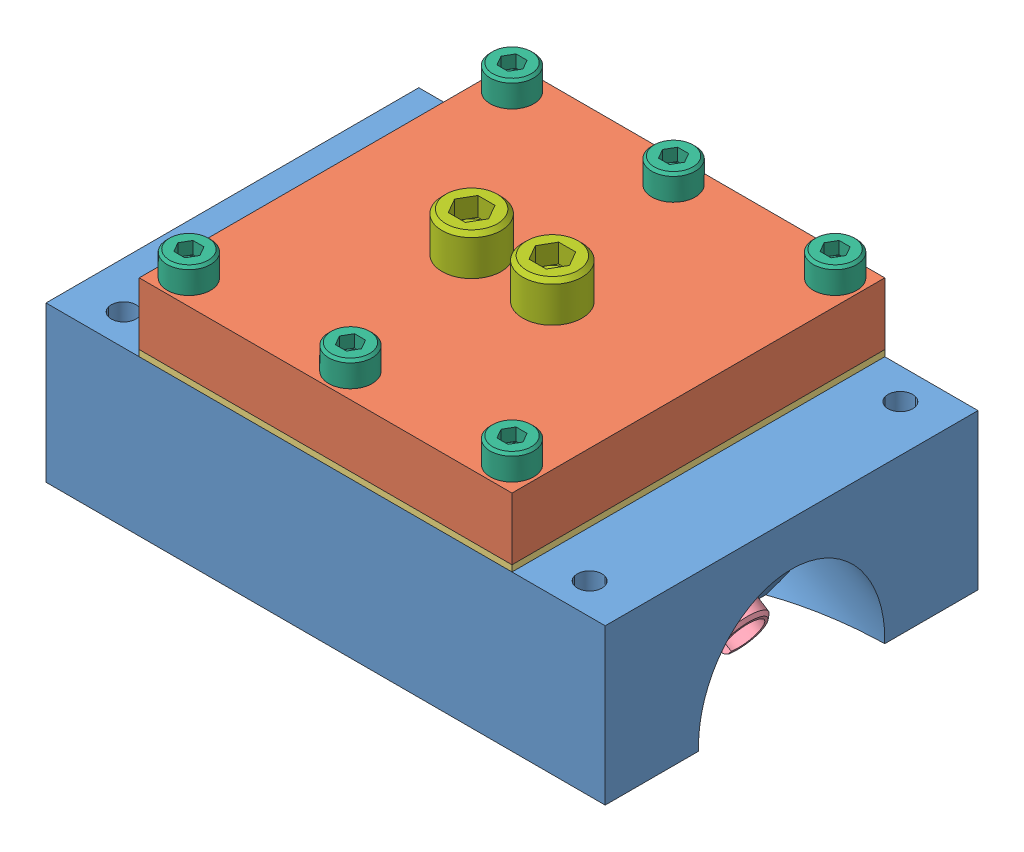
SolidWorks assembly assembly of final, configuration Default. Lengths in mm.
Overall size (90 48.33 60).
13 component instances, 7 part files, 27 mates.
Components (placement in the parent):
- base part 3-1: base part 3 [Default] at (-24.9523 7.0042 -0.1274) size (90 25.13 60)
- top part3-1: top part3 [Default] at (-24.9523 33.0042 -0.1274) size (60 10 60)
- gasket2-1: gasket2 [Default] at (-24.9523 32.0042 -0.1274) size (60 1 60)
- colimator-1: colimator [Default] at (1.7735 18.1321 -0.1274) x (0.25 0.433013 0.866025) z (-0.866025 0.5 0) size (11 11 20.5)
- detector-1: detector [Default] at (-24.9523 24.294 -0.1274) x (0.477197 0 0.878796) z (-0.878796 0 0.477197) size (13.46 23.78 13.46)
- socket head cap screw_am-31: socket head cap screw_am [B18.3.1M - 4 x 0.7 x 20 Hex SHCS -- 20SHX] at (-24.9523 47.0042 -26.1274) x (0 -1 0) z (0 0 1) size (24 7 7)
- socket head cap screw_am-32: socket head cap screw_am [B18.3.1M - 4 x 0.7 x 20 Hex SHCS -- 20SHX] at (-50.9523 47.0042 -26.1274) x (0 -1 0) z (0 0 1) size (24 7 7)
- socket head cap screw_am-33: socket head cap screw_am [B18.3.1M - 4 x 0.7 x 20 Hex SHCS -- 20SHX] at (1.0477 47.0042 -26.1274) x (0 -1 0) z (0 0 1) size (24 7 7)
- socket head cap screw_am-34: socket head cap screw_am [B18.3.1M - 4 x 0.7 x 20 Hex SHCS -- 20SHX] at (1.0477 47.0042 25.8726) x (0 -1 0) z (0 0 1) size (24 7 7)
- socket head cap screw_am-35: socket head cap screw_am [B18.3.1M - 4 x 0.7 x 20 Hex SHCS -- 20SHX] at (-24.9523 47.0042 25.8726) x (0 -1 0) z (0 0 1) size (24 7 7)
- socket head cap screw_am-36: socket head cap screw_am [B18.3.1M - 4 x 0.7 x 20 Hex SHCS -- 20SHX] at (-50.9523 47.0042 25.8726) x (0 -1 0) z (0 0 1) size (24 7 7)
- socket head cap screw_ai-3: socket head cap screw_ai [HX-SHCS 0.25-28x0.3125x0.3125-S] at (-31.4523 49.3542 -0.1274) x (0 -1 0) z (0 0 1) size (14.29 9.53 9.53)
- socket head cap screw_ai-4: socket head cap screw_ai [HX-SHCS 0.25-28x0.3125x0.3125-S] at (-18.4523 49.3542 -0.1274) x (0 -1 0) z (0 0 1) size (14.29 9.53 9.53)
Mates (geometry in assembly coordinates):
- Coincident1: coincident anti-aligned: plane of base part 3-1 through (-24.9523 32.0042 -0.1274) normal (0 1 0); plane of gasket2-1 through (-24.9523 32.0042 -0.1274) normal (0 -1 0)
- Coincident2: coincident anti-aligned: plane of top part3-1 through (-24.9523 33.0042 -0.1274) normal (0 -1 0); plane of gasket2-1 through (-24.9523 33.0042 -0.1274) normal (0 1 0)
- Concentric6: concentric anti-aligned: circle of base part 3-1; circle of detector-1
- Coincident4: coincident anti-aligned: plane of base part 3-1 through (-24.9523 24.8042 -0.1274) normal (0 -1 0); plane of detector-1 through (-28.0889 24.8042 -0.7633) normal (0 1 0)
- Coincident5: coincident anti-aligned: plane of base part 3-1 through (-4.9906 22.0374 -0.1274) normal (0.866025 -0.5 0); plane of colimator-1 through (-7.3721 17.9124 2.6226) normal (-0.866025 0.5 0)
- Concentric7: concentric aligned: circle of base part 3-1; circle of colimator-1
- Parallel2: parallel anti-aligned: plane of base part 3-1 through (-24.9523 32.0042 -0.1274) normal (0 1 0); plane of gasket2-1 through (-24.9523 32.0042 -0.1274) normal (0 -1 0)
- Concentric20: concentric aligned: cylinder of base part 3-1 through (1.0477 32.0042 -26.1274) axis (0 1 0) radius 1.65; cylinder of gasket2-1 through (1.0477 33.0042 -26.1274) axis (0 1 0) radius 1.65
- Coincident19: coincident aligned: circle of base part 3-1; cylinder of gasket2-1 through (-50.9523 33.0042 25.8726) axis (0 1 0) radius 1.65
- Concentric21: concentric anti-aligned: cylinder of top part3-1 through (-50.9523 33.0042 25.8726) axis (0 -1 0) radius 1.65; cylinder of gasket2-1 through (-50.9523 33.0042 25.8726) axis (0 1 0) radius 1.65
- Concentric741: concentric anti-aligned: cylinder of top part3-1 through (-24.9523 33.0042 -26.1274) axis (0 -1 0) radius 1.65; cylinder of socket head cap screw_am-31 through (-24.9523 78.7542 -26.1274) axis (0 1 0) radius 3.5
- Coincident691: coincident anti-aligned: plane of top part3-1 through (-24.9523 43.0042 -0.1274) normal (0 1 0); plane of socket head cap screw_am-31 through (-21.4523 43.0042 -26.1274) normal (0 -1 0)
- Concentric751: concentric anti-aligned: cylinder of top part3-1 through (-50.9523 33.0042 -26.1274) axis (0 -1 0) radius 1.65; cylinder of socket head cap screw_am-32 through (-50.9523 78.7542 -26.1274) axis (0 1 0) radius 3.5
- Coincident701: coincident anti-aligned: plane of top part3-1 through (-24.9523 43.0042 -0.1274) normal (0 1 0); plane of socket head cap screw_am-32 through (-47.4523 43.0042 -26.1274) normal (0 -1 0)
- Concentric761: concentric anti-aligned: cylinder of top part3-1 through (1.0477 33.0042 -26.1274) axis (0 -1 0) radius 1.65; cylinder of socket head cap screw_am-33 through (1.0477 78.7542 -26.1274) axis (0 1 0) radius 3.5
- Coincident711: coincident anti-aligned: plane of top part3-1 through (-24.9523 43.0042 -0.1274) normal (0 1 0); plane of socket head cap screw_am-33 through (4.5477 43.0042 -26.1274) normal (0 -1 0)
- Concentric771: concentric anti-aligned: cylinder of top part3-1 through (1.0477 33.0042 25.8726) axis (0 -1 0) radius 1.65; cylinder of socket head cap screw_am-34 through (1.0477 78.7542 25.8726) axis (0 1 0) radius 3.5
- Coincident721: coincident anti-aligned: plane of top part3-1 through (-24.9523 43.0042 -0.1274) normal (0 1 0); plane of socket head cap screw_am-34 through (4.5477 43.0042 25.8726) normal (0 -1 0)
- Concentric781: concentric anti-aligned: cylinder of top part3-1 through (-24.9523 33.0042 25.8726) axis (0 -1 0) radius 1.65; cylinder of socket head cap screw_am-35 through (-24.9523 78.7542 25.8726) axis (0 1 0) radius 3.5
- Coincident731: coincident anti-aligned: plane of top part3-1 through (-24.9523 43.0042 -0.1274) normal (0 1 0); plane of socket head cap screw_am-35 through (-21.4523 43.0042 25.8726) normal (0 -1 0)
- Concentric791: concentric anti-aligned: cylinder of top part3-1 through (-50.9523 33.0042 25.8726) axis (0 -1 0) radius 1.65; cylinder of socket head cap screw_am-36 through (-50.9523 78.7542 25.8726) axis (0 1 0) radius 3.5
- Coincident741: coincident anti-aligned: plane of top part3-1 through (-24.9523 43.0042 -0.1274) normal (0 1 0); plane of socket head cap screw_am-36 through (-47.4523 43.0042 25.8726) normal (0 -1 0)
- Concentric801: concentric aligned: cylinder of top part3-1 through (-31.4523 43.0042 -0.1274) axis (0 1 0) radius 2.7051; cylinder of socket head cap screw_ai-3 through (-31.4523 81.1042 -0.1274) axis (0 1 0) radius 4.7625
- Coincident751: coincident anti-aligned: plane of top part3-1 through (-24.9523 43.0042 -0.1274) normal (0 1 0); plane of socket head cap screw_ai-3 through (-26.6898 43.0042 -0.1274) normal (0 -1 0)
- Concentric811: concentric aligned: cylinder of top part3-1 through (-18.4523 43.0042 -0.1274) axis (0 1 0) radius 2.7051; cylinder of socket head cap screw_ai-4 through (-18.4523 81.1042 -0.1274) axis (0 1 0) radius 4.7625
- Coincident761: coincident anti-aligned: plane of top part3-1 through (-24.9523 43.0042 -0.1274) normal (0 1 0); plane of socket head cap screw_ai-4 through (-13.6898 43.0042 -0.1274) normal (0 -1 0)
- Concentric82: concentric anti-aligned: circle of top part3-1; circle of gasket2-1
